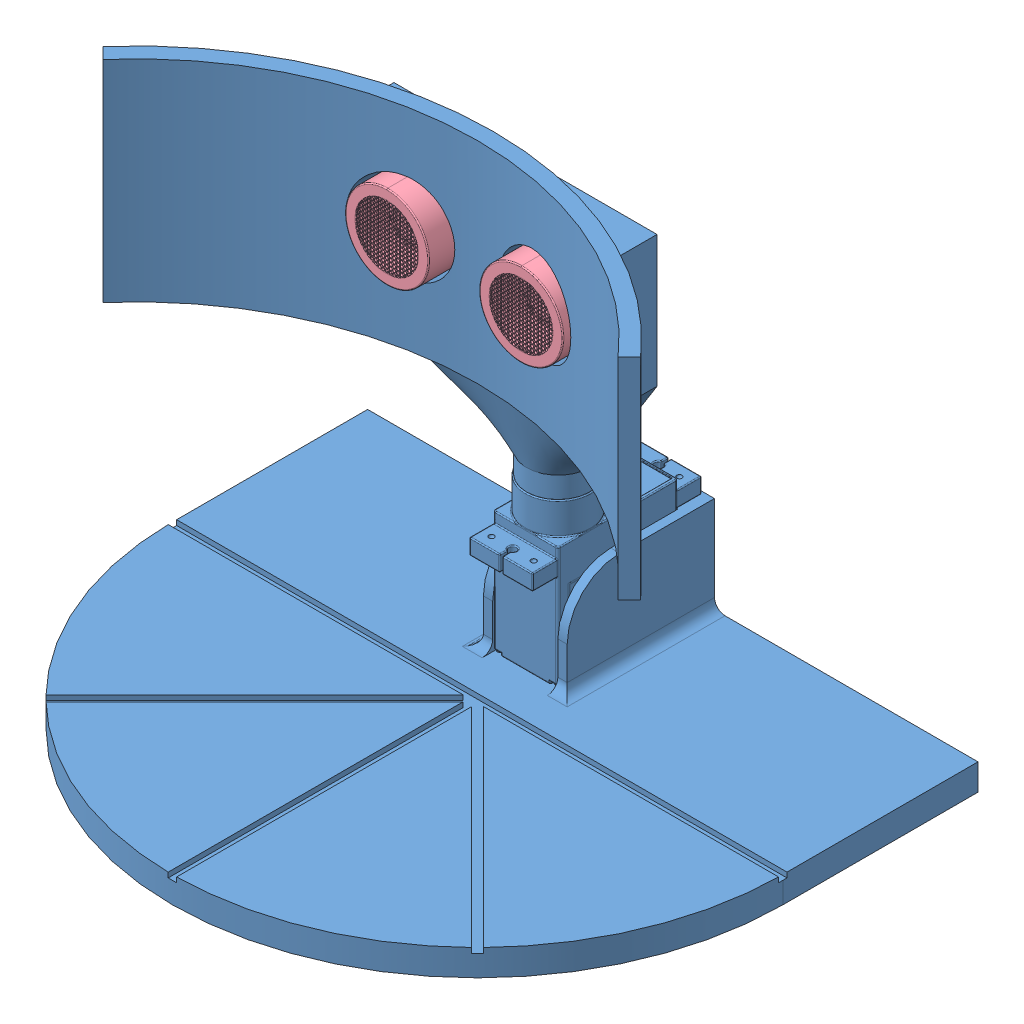
SolidWorks assembly Projeto Radar, configuration Default. Lengths in mm.
Overall size (116 96.8 95.1).
49 component instances, 19 part files, 6 mates.
Components (placement in the parent):
- Antena-1: Antena [Default] at (17.4587 24.8118 68.1329) size (116 96.8 95.1)
- HC-SR04-1: HC-SR04 [Default] at (17.4587 24.8118 24.0329) x (1 0 0) z (0 -1 0) size (45.5 21.95 20.5)
  - HC-SR04.STEP-1: HC-SR04.STEP [Default] at origin size (45.5 21.95 20.5)
    - HC-SR04board.STEP-1: HC-SR04board.STEP [Default] at origin size (45.5 1.61 20.5)
    - solder.STEP-1: solder.STEP [Default] at (-3.8014 1.6 8.5727) size (1.17 0.65 1.17)
    - solder.STEP-2: solder.STEP [Default] at (-1.2614 1.6 8.5727) size (1.17 0.65 1.17)
    - solder.STEP-3: solder.STEP [Default] at (1.2786 1.6 8.5727) size (1.17 0.65 1.17)
    - solder.STEP-4: solder.STEP [Default] at (3.8186 1.6 8.5727) size (1.17 0.65 1.17)
    - Emitter.STEP-1: Emitter.STEP [Default] at (-12.75 1.6 0) size (15.9 15.2 15.9)
    - Emitter.STEP-2: Emitter.STEP [Default] at (12.75 1.6 0) size (15.9 15.2 15.9)
    - CrystalOscillator.STEP-1: CrystalOscillator.STEP [Default] at (0 1.6 -7.5) size (13.3 6.4 4.5)
    - solder.STEP-5: solder.STEP [Default] at (-2.0167 0 -7.5286) x (-0.837169 0 -0.546944) z (-0.546944 0 0.837169) size (1.17 0.65 1.17)
    - solder.STEP-6: solder.STEP [Default] at (1.9833 0 -7.5286) x (-0.837169 0 -0.546944) z (-0.546944 0 0.837169) size (1.17 0.65 1.17)
    - smdChip14pin.STEP-1: smdChip14pin.STEP [Default] at (22.25 -0.725 0) x (0 0 -1) z (-1 0 0) size (7.3 1.22 8.75)
    - smdChip14pin.STEP-2: smdChip14pin.STEP [Default] at (4.375 -0.725 0) x (0 0 -1) z (-1 0 0) size (7.3 1.22 8.75)
    - smdChip16pin.STEP-1: smdChip16pin.STEP [Default] at (-18.6 -0.725 5) x (1 0 0) z (0 0 -1) size (7.3 1.22 10)
    - smdceramiccapacitor.STEP-1: smdceramiccapacitor.STEP [Default] at (17.8499 0 -5.5522) x (0 0 -1) z (-1 0 0) size (2.52 0.61 1.3)
    - smdceramiccapacitor.STEP-2: smdceramiccapacitor.STEP [Default] at (17.8499 0 5.585) x (0 0 -1) z (-1 0 0) size (2.52 0.61 1.3)
    - smdceramiccapacitor.STEP-3: smdceramiccapacitor.STEP [Default] at (15.2359 0 8.7006) x (-1 0 0) z (0 0 1) size (2.52 0.61 1.3)
    - smdceramiccapacitor.STEP-4: smdceramiccapacitor.STEP [Default] at (8.3844 0 0.0383) x (-1 0 0) z (0 0 1) size (2.52 0.61 1.3)
    - smdceramiccapacitor.STEP-5: smdceramiccapacitor.STEP [Default] at (8.3844 0 -4.7577) x (-1 0 0) z (0 0 1) size (2.52 0.61 1.3)
    - smdceramiccapacitor.STEP-6: smdceramiccapacitor.STEP [Default] at (8.3844 0 -2.3108) x (-1 0 0) z (0 0 1) size (2.52 0.61 1.3)
    - smdceramiccapacitor.STEP-7: smdceramiccapacitor.STEP [Default] at (-7.8145 0 -2.3108) x (-1 0 0) z (0 0 1) size (2.52 0.61 1.3)
    - smdResistor753.STEP-1: smdResistor753.STEP [Default] at (20.6199 0 5.0565) x (-1 0 0) z (0 0 1) size (2.53 0.63 1.31)
    - smdResistor753.STEP-2: smdResistor753.STEP [Default] at (-7.7732 0 -0.1429) x (-1 0 0) z (0 0 1) size (2.53 0.63 1.31)
    - smdResistor753.STEP-3: smdResistor753.STEP [Default] at (20.6199 0 -4.936) x (-1 0 0) z (0 0 1) size (2.53 0.63 1.31)
    - smdResistor392.STEP-1: smdResistor392.STEP [Default] at (-18.578 0 -6.4389) x (-1 0 0) z (0 0 1) size (2.53 0.63 1.31)
    - smdResistor103.STEP-1: smdResistor103.STEP [Default] at (-18.578 0 6.8031) x (-1 0 0) z (0 0 1) size (2.53 0.63 1.31)
    - smdResistor124.STEP-1: smdResistor124.STEP [Default] at (-7.7732 0 1.8639) x (-1 0 0) z (0 0 1) size (2.53 0.63 1.31)
    - smdResistor103.STEP-2: smdResistor103.STEP [Default] at (-7.7732 0 3.8148) x (-1 0 0) z (0 0 1) size (2.53 0.63 1.31)
    - smdResistor103.STEP-3: smdResistor103.STEP [Default] at (-7.7732 0 5.8773) x (-1 0 0) z (0 0 1) size (2.53 0.63 1.31)
    - smdResistor335.STEP-1: smdResistor335.STEP [Default] at (-7.7732 0 -4.435) x (-1 0 0) z (0 0 1) size (2.53 0.63 1.31)
    - smdResistor102.STEP-1: smdResistor102.STEP [Default] at (8.4383 0 5.8773) x (-1 0 0) z (0 0 1) size (2.53 0.63 1.31)
    - smdResistor103.STEP-4: smdResistor103.STEP [Default] at (8.4383 0 3.8148) x (-1 0 0) z (0 0 1) size (2.53 0.63 1.31)
    - smdResistor563.STEP-1: smdResistor563.STEP [Default] at (8.4383 0 1.8639) x (-1 0 0) z (0 0 1) size (2.53 0.63 1.31)
    - smdResistor103.STEP-5: smdResistor103.STEP [Default] at (8.4383 0 -6.6305) x (-1 0 0) z (0 0 1) size (2.53 0.63 1.31)
    - smdResistor622.STEP-1: smdResistor622.STEP [Default] at (9.6708 0 8.6421) x (-1 0 0) z (0 0 1) size (2.53 0.63 1.31)
    - smdResistor124.STEP-2: smdResistor124.STEP [Default] at (10.2038 0 -8.7291) x (-1 0 0) z (0 0 1) size (2.53 0.63 1.31)
    - smdResistor412.STEP-1: smdResistor412.STEP [Default] at (14.0013 0 -8.7291) x (-1 0 0) z (0 0 1) size (2.53 0.63 1.31)
    - smdResistor103.STEP-6: smdResistor103.STEP [Default] at (17.3324 0 -8.7291) x (-1 0 0) z (0 0 1) size (2.53 0.63 1.31)
    - solder.STEP-7: solder.STEP [Default] at (-12.8084 0 -5.0269) x (-0.837169 0 -0.546944) z (-0.546944 0 0.837169) size (1.17 0.65 1.17)
    - solder.STEP-8: solder.STEP [Default] at (-12.8084 0 5.0295) x (-0.837169 0 -0.546944) z (-0.546944 0 0.837169) size (1.17 0.65 1.17)
    - solder.STEP-9: solder.STEP [Default] at (12.7872 0 5.0295) x (-0.837169 0 -0.546944) z (-0.546944 0 0.837169) size (1.17 0.65 1.17)
    - solder.STEP-10: solder.STEP [Default] at (12.7872 0 -5.0269) x (-0.837169 0 -0.546944) z (-0.546944 0 0.837169) size (1.17 0.65 1.17)
    - headerMale.STEP-1: headerMale.STEP [Default] at (3.81 0 8.58) x (-1 0 0) z (0 0 1) size (2.54 11.1 2.54)
    - headerMale.STEP-2: headerMale.STEP [Default] at (1.27 0 8.58) x (-1 0 0) z (0 0 1) size (2.54 11.1 2.54)
    - headerMale.STEP-3: headerMale.STEP [Default] at (-1.27 0 8.58) x (-1 0 0) z (0 0 1) size (2.54 11.1 2.54)
    - headerMale.STEP-4: headerMale.STEP [Default] at (-3.81 0 8.58) x (-1 0 0) z (0 0 1) size (2.54 11.1 2.54)
- Tower-Pro-MG90S-2: Tower-Pro-MG90S [Valor predeterminado] at (17.4587 -46.4882 12.6329) x (0 0 1) z (-1 0 0) size (32.1 32.51 12.5)
Mates (geometry in assembly coordinates):
- Width3: width anti-aligned: plane of HC-SR04-1/HC-SR04.STEP-1/HC-SR04board.STEP-1 through (-5.2913 35.0618 25.6329) normal (0 1 0); plane of Antena-1 through (-5.2913 14.5618 25.6329) normal (0 -1 0); plane of HC-SR04-1/HC-SR04.STEP-1/HC-SR04board.STEP-1 through (40.6587 35.5118 29.1329) normal (0 -1 0); plane of Antena-1 through (40.6587 14.1118 29.1329) normal (0 1 0)
- Width4: width anti-aligned: plane of HC-SR04-1/HC-SR04.STEP-1/HC-SR04board.STEP-1 through (40.2087 14.5618 25.6329) normal (1 0 0); plane of Antena-1 through (-5.2913 14.5618 25.6329) normal (-1 0 0); plane of HC-SR04-1/HC-SR04.STEP-1/HC-SR04board.STEP-1 through (40.6587 35.5118 29.1329) normal (-1 0 0); plane of Antena-1 through (-5.7413 35.5118 29.1329) normal (1 0 0)
- Coincident1: coincident anti-aligned: plane of Antena-1 through (17.4587 24.8118 29.1329) normal (0 0 -1); plane of HC-SR04-1/HC-SR04.STEP-1/CrystalOscillator.STEP-1 through (14.3087 32.3118 29.1329) normal (0 0 1)
- Coincident3: coincident anti-aligned: plane of Antena-1 through (17.4587 24.8118 24.0329) normal (0 0 -1); plane of Tower-Pro-MG90S-2 through (23.6587 -23.6882 24.0329) normal (0 0 1)
- Width5: width aligned: plane of Tower-Pro-MG90S-2 through (23.6587 -23.6882 1.2329) normal (1 0 0); plane of Antena-1 through (11.2587 -23.6882 1.2329) normal (-1 0 0); plane of Tower-Pro-MG90S-2 through (42.4587 37.3118 26.1329) normal (1 0 0); plane of Antena-1 through (-7.5413 37.3118 34.8978) normal (-1 0 0)
- Distance2: distance = 30 mm: plane of Tower-Pro-MG90S-2 through (17.3837 -17.6882 11.4734) normal (0 1 0); plane of Antena-1 through (17.4587 12.3118 98.0989) normal (0 -1 0)
